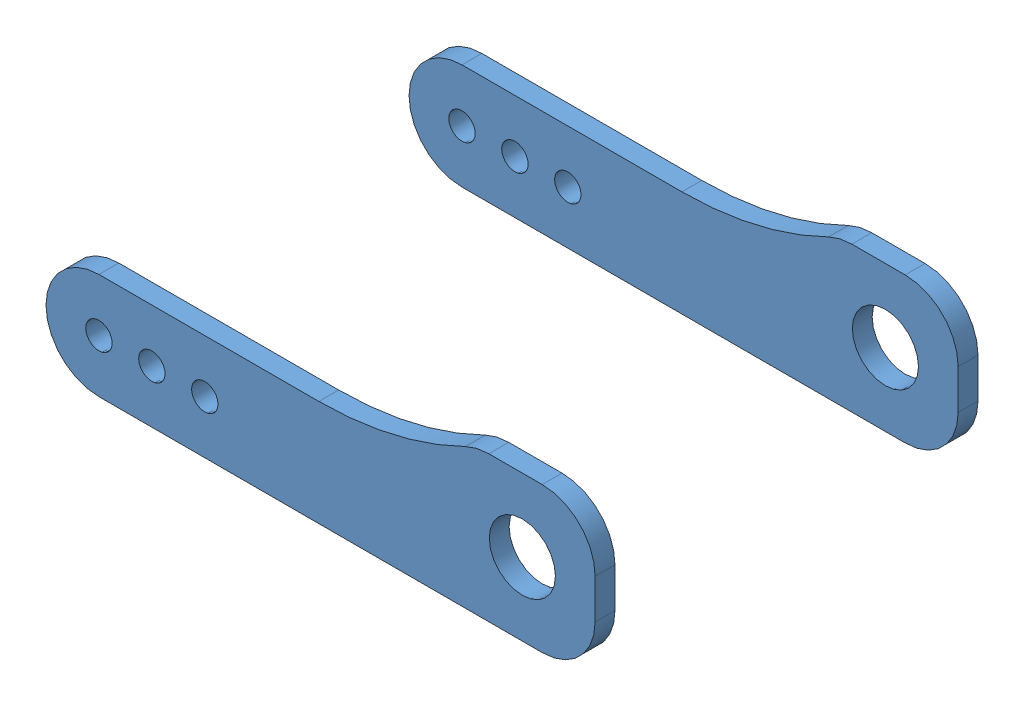
SolidWorks assembly Assem2, configuration Default. Lengths in mm.
Overall size (83 22 57.88).
2 component instances, 1 part files, 2 mates.
Components (placement in the parent):
- joint_lower2-1: joint_lower2 [Default] at origin size (83 22 3)
- joint_lower2-2: joint_lower2 [Default] at (0 0 54.8752) size (83 22 3)
Mates (geometry in assembly coordinates):
- Concentric1: concentric aligned: cylinder of joint_lower2-1 through (64 3 -14.1421) axis (0 0 1) radius 5; cylinder of joint_lower2-2 through (64 3 40.7331) axis (0 0 1) radius 5
- Parallel1: parallel aligned: plane of joint_lower2-1 through (0 0 0) normal (0 1 0); plane of joint_lower2-2 through (0 0 54.8752) normal (0 1 0)
